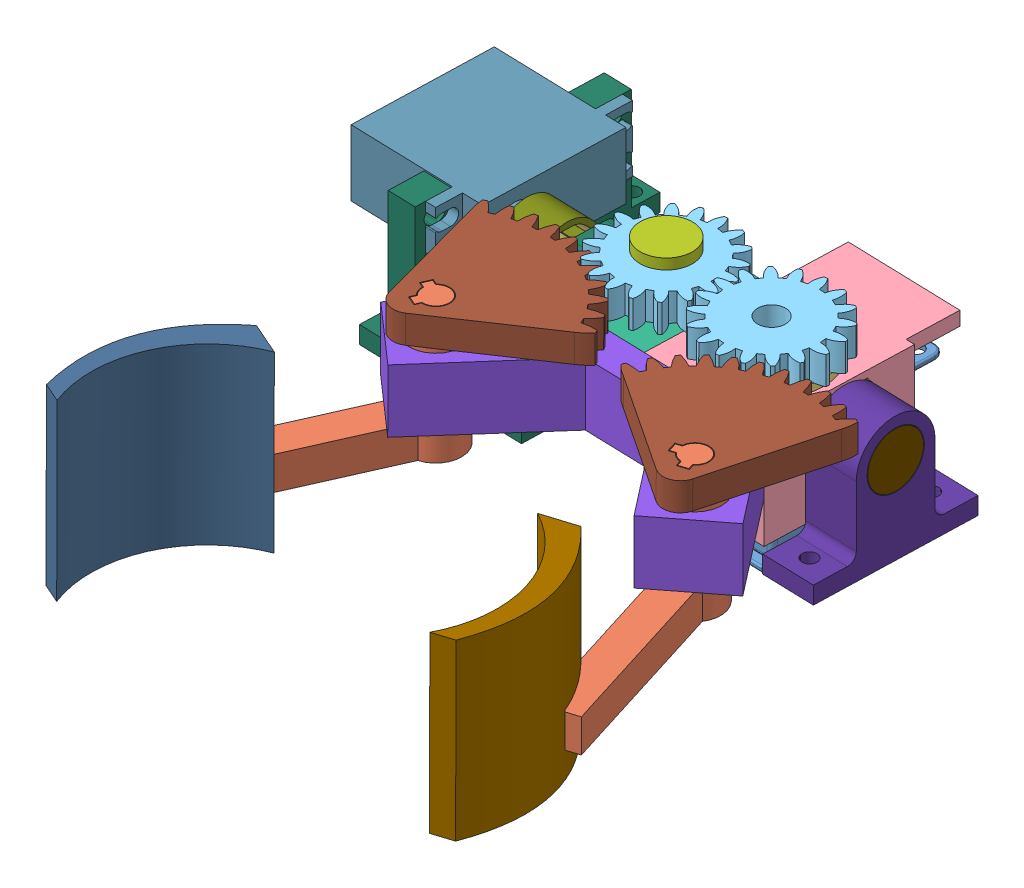
SolidWorks assembly grabber, configuration Default. Lengths in mm.
Overall size (169.93 60.06 188.53).
21 component instances, 18 part files, 50 mates.
Components (placement in the parent):
- servo-1: servo [Default] at (27.3766 37.9573 15.2032) x (0.029481 -0.000434 -0.999565) z (0.999565 0 0.029481) size (56.4 46.15 25.5)
- arm_things-1: arm_things [Default] at (68.0393 35.6063 98.6432) x (-0.953787 0.000799 0.300482) z (-0.300483 -0.002298 -0.953784) size (14.9 36.5 66.45)
- arm_things-2: arm_things [Default] at (-29.4467 35.6051 95.2471) x (-0.915399 -0.000913 -0.402546) z (0.402547 -0.002255 -0.915397) size (14.9 36.5 66.45)
- smol_white_disc_thing-1: smol_white_disc_thing [Default] at (37.0542 61.332 26.2832) x (0.993414 -0.000062 -0.11458) z (0.11458 0.00043 0.993414) size (30 3.9 30)
- servo_mount-1: servo_mount [Default] at (18.3812 44.8063 14.9167) x (0.999565 0 0.029481) z (-0.029481 0.002433 0.999562) size (35.55 36.2 57.02)
- spur gear_iso-3: spur gear_iso [ISO - Spur gear 1.75M 18T 20PA 8mmFW ---S18A75H50L8.0N] at (37.0542 65.232 26.2815) x (0.000013 1 -0.000434) z (-0.997235 -0.000019 -0.074312) size (8 34.62 35)
- spur gear_iso-4: spur gear_iso [ISO - Spur gear 1.75M 18T 20PA 8mmFW ---S18A75H50L8.0N] at (5.8572 64.9327 25.3831) x (0.000072 0.999997 -0.002432) z (0.987046 0.000319 0.160439) size (8 34.62 35)
- servo_primary_gear_mount_thingy-1: servo_primary_gear_mount_thingy [Default] at (8.2401 58.24 43.1074) x (-0.999565 0 -0.029481) z (0.029481 -0.002433 -0.999562) size (27.5 27.5 35)
- pin_dongley-1: pin_dongley [Default] at (5.8279 67.515 27.4291) x (0.999897 -0.000037 0.01435) z (-0.014349 0.002433 0.999894) size (15 17 15)
- big_gear_sticky_thing-1: big_gear_sticky_thing [Default] at (22.8275 45.0127 58.8056) x (0.999565 0 0.029481) z (-0.029481 0.002433 0.999562) size (107.35 18 41.03)
- left_grabby_hand-1: left_grabby_hand [Default] at (41.9504 28.2179 143.7732) x (-0.953787 0.000799 0.300482) z (-0.300483 -0.002298 -0.953784) size (16.77 50 47.38)
- right_grabby_hand-1: right_grabby_hand [Default] at (-8.4259 28.2196 142.9495) x (-0.915399 -0.000913 -0.402546) z (0.402547 -0.002255 -0.915397) size (16.77 50 47.38)
- big_boi_gear_left-1: big_boi_gear_left [Default] at (60.0564 65.2677 59.5235) x (0.000072 0.999997 -0.002432) z (0.953787 -0.000799 -0.300482) size (8 45.26 52.07)
- big_boi_gear_left-2: big_boi_gear_left [Default] at (-9.718 65.2752 60.5437) x (0.000072 0.999997 -0.002432) z (0.915399 0.000913 0.402546) size (8 45.26 52.07)
- right_side_axle-1: right_side_axle [Default] at (-1.8251 52.724 21.6147) x (-0.999565 0 -0.029481) z (0.029481 -0.002433 -0.999562) size (26 15.6 15.6)
- seamuing_25kg_servo_fitting-1: seamuing_25kg_servo_fitting [Default] at (-39.4398 52.7576 34.1111) x (0.000072 0.999997 -0.002432) z (0.029481 -0.002433 -0.999562) size (14.8 6 35)
- seamuing_25kg_servo_rough-1: seamuing_25kg_servo_rough [Default] at (-81.4601 52.7211 8.061) x (0.029481 -0.000265 -0.999565) z (-0.000008 -1 0.000265) size (55 47 19)
- axle_mount_right-2: axle_mount_right [Default] at (-59.5969 50.8365 13.0242) x (0.029481 -0.000265 -0.999565) z (0.999565 0 0.029481) size (76.4 34.5 48)
- servo_fitting_attachment-1: servo_fitting_attachment [Default] at (-27.0382 52.724 20.6709) x (-0.999565 0 -0.029481) z (0.029481 -0.002433 -0.999562) size (17 18.5 39.79)
- axle_mount_left-1: axle_mount_left [Default] at (55.2001 40.224 23.2966) x (0.999565 0 0.029481) z (-0.029481 0 0.999565) size (15 36 46)
- axle_left-1: axle_left [Default] at (47.2036 52.724 23.0607) x (0.999565 0 0.029481) z (-0.029481 0.002433 0.999562) size (23 15.6 15.6)
Mates (geometry in assembly coordinates):
- Coincident8: coincident anti-aligned: line of servo-1 through (37.0542 64.362 26.2819) axis (-0.000013 -1 0.000434); line of smol_white_disc_thing-1 through (37.0542 61.332 26.2832) axis (0.000013 1 -0.000434)
- Coincident10: coincident anti-aligned: plane of servo-1 through (37.0542 64.362 26.2819) normal (0.000013 1 -0.000434); plane of smol_white_disc_thing-1 through (37.0542 64.362 26.2819) normal (-0.000013 -1 0.000434)
- Coincident11: coincident aligned: line of servo-1 through (24.6003 30.6467 -9.3861) axis (-0.999565 0 -0.029481); line of servo_mount-1 through (23.101 30.6467 -9.4304) axis (-0.999565 0 -0.029481)
- Distance1: distance = 0.1 mm: line of servo_mount-1 through (21.6558 30.766 39.5682) axis (-0.999565 0 -0.029481); line of servo-1 through (23.1558 30.6679 39.5926) axis (-0.999565 0 -0.029481)
- Coincident12: coincident anti-aligned: plane of servo-1 through (22.3788 37.9573 15.0558) normal (-0.999565 0 -0.029481); plane of servo_mount-1 through (22.3794 44.8063 15.0346) normal (0.999565 0 0.029481)
- Coincident15: coincident anti-aligned: line of smol_white_disc_thing-1 through (37.0542 63.232 26.2824) axis (0.000013 1 -0.000434); line of spur gear_iso-3 through (37.0543 73.232 26.278) axis (-0.000013 -1 0.000434)
- Coincident16: coincident anti-aligned: plane of smol_white_disc_thing-1 through (37.0542 65.232 26.2815) normal (0.000013 1 -0.000434); plane of spur gear_iso-3 through (37.0542 65.232 26.2815) normal (-0.000013 -1 0.000434)
- Coincident17: coincident aligned: line of servo_mount-1 through (19.223 62.8368 -13.6249) axis (-0.029481 0.002433 0.999562); line of servo_primary_gear_mount_thingy-1 through (18.5738 62.8904 8.3855) axis (-0.029481 0.002433 0.999562)
- Coincident18: coincident aligned: line of servo_mount-1 through (17.542 62.9756 43.3702) axis (-0.000072 -0.999997 0.002432); line of servo_primary_gear_mount_thingy-1 through (17.542 62.9756 43.3702) axis (-0.000072 -0.999997 0.002432)
- Coincident23: coincident anti-aligned: plane of servo_primary_gear_mount_thingy-1 through (5.8568 59.9327 25.3952) normal (0.000072 0.999997 -0.002432); plane of pin_dongley-1 through (5.8037 59.9417 29.0948) normal (-0.000072 -0.999997 0.002432)
- Coincident25: coincident aligned: line of servo_primary_gear_mount_thingy-1 through (5.8568 59.9327 25.3952) axis (0.000072 0.999997 -0.002432); line of pin_dongley-1 through (5.8568 59.9327 25.3952) axis (0.000072 0.999997 -0.002432)
- Coincident29: coincident anti-aligned: line of spur gear_iso-4 through (5.8577 72.9327 25.3636) axis (-0.000072 -0.999997 0.002432); line of pin_dongley-1 through (5.8568 59.9327 25.3952) axis (0.000072 0.999997 -0.002432)
- Coincident30: coincident anti-aligned: plane of spur gear_iso-4 through (5.8572 64.9327 25.3831) normal (-0.000072 -0.999997 0.002432); plane of servo_primary_gear_mount_thingy-1 through (5.8572 64.9327 25.3831) normal (0.000072 0.999997 -0.002432)
- GearMate1: gear = 18 : 18 mm: line of spur gear_iso-3 through (37.0543 73.232 26.278) axis (-0.000013 -1 0.000434); line of spur gear_iso-4 through (5.8577 72.9327 25.3636) axis (-0.000072 -0.999997 0.002432)
- Coincident33: coincident aligned: line of servo_mount-1 through (53.0765 62.9756 44.4182) axis (-0.000072 -0.999997 0.002432); line of big_gear_sticky_thing-1 through (53.0765 62.9756 44.4182) axis (-0.000072 -0.999997 0.002432)
- Coincident34: coincident aligned: line of servo_mount-1 through (53.0765 62.9756 44.4182) axis (-0.999565 0 -0.029481); line of big_gear_sticky_thing-1 through (53.0765 62.9756 44.4182) axis (-0.999565 0 -0.029481)
- Coincident43: coincident anti-aligned: line of arm_things-1 through (59.1757 45.0385 70.4834) axis (0.000072 0.999997 -0.002432); line of big_gear_sticky_thing-1 through (59.177 63.0384 70.4396) axis (-0.000072 -0.999997 0.002432)
- Coincident45: coincident anti-aligned: plane of arm_things-1 through (68.04 45.1063 98.6201) normal (0.000072 0.999997 -0.002432); plane of big_gear_sticky_thing-1 through (22.8275 45.0127 58.8056) normal (-0.000072 -0.999997 0.002432)
- Coincident46: coincident anti-aligned: line of arm_things-1 through (72.3737 45.1779 128.184) axis (-0.000072 -0.999997 0.002432); line of left_grabby_hand-1 through (72.3731 35.6779 128.2071) axis (0.000072 0.999997 -0.002432)
- Coincident47: coincident anti-aligned: line of arm_things-1 through (56.3691 35.5555 77.4079) axis (0.300483 0.002298 0.953784); line of left_grabby_hand-1 through (72.3731 35.6779 128.2071) axis (-0.300483 -0.002298 -0.953784)
- Coincident48: coincident aligned: line of arm_things-2 through (-36.973 45.1759 124.1403) axis (-0.000072 -0.999997 0.002432); line of right_grabby_hand-1 through (-36.973 45.6759 124.1391) axis (-0.000072 -0.999997 0.002432)
- Coincident49: coincident aligned: line of arm_things-2 through (-36.9737 35.6759 124.1634) axis (0.402547 -0.002255 -0.915397); line of right_grabby_hand-1 through (-36.9737 35.6759 124.1634) axis (0.402547 -0.002255 -0.915397)
- Coincident50: coincident anti-aligned: line of arm_things-2 through (-17.5709 45.0385 68.2198) axis (0.000072 0.999997 -0.002432); line of big_gear_sticky_thing-1 through (-17.5696 63.0384 68.1761) axis (-0.000072 -0.999997 0.002432)
- Coincident51: coincident anti-aligned: plane of arm_things-2 through (-29.446 45.105 95.224) normal (0.000072 0.999997 -0.002432); plane of big_gear_sticky_thing-1 through (22.8275 45.0127 58.8056) normal (-0.000072 -0.999997 0.002432)
- Coincident52: coincident aligned: line of arm_things-1 through (59.1777 72.0384 70.4177) axis (-0.000072 -0.999997 0.002432); line of big_boi_gear_left-1 through (59.1777 72.0384 70.4177) axis (-0.000072 -0.999997 0.002432)
- Coincident54: coincident anti-aligned: plane of arm_things-1 through (59.1771 64.0384 70.4372) normal (0.000072 0.999997 -0.002432); plane of big_boi_gear_left-1 through (59.1771 64.0384 70.4372) normal (-0.000072 -0.999997 0.002432)
- Parallel1: parallel aligned: line of arm_things-1 through (59.4915 72.0513 75.7401) axis (0.953787 -0.000799 -0.300482); line of big_boi_gear_left-1 through (59.3696 72.052 76.0189) axis (0.953787 -0.000799 -0.300482)
- Coincident57: coincident aligned: line of arm_things-1 through (59.1777 72.0384 70.4177) axis (-0.000072 -0.999997 0.002432); line of big_boi_gear_left-1 through (59.1777 72.0384 70.4177) axis (-0.000072 -0.999997 0.002432)
- GearMate6: gear = 38 : 18 mm: line of spur gear_iso-3 through (37.0543 73.232 26.278) axis (-0.000013 -1 0.000434); line of big_boi_gear_left-1 through (59.1777 72.0384 70.4177) axis (-0.000072 -0.999997 0.002432)
- Coincident59: coincident aligned: line of arm_things-2 through (-17.569 72.0384 68.1542) axis (-0.000072 -0.999997 0.002432); line of big_boi_gear_left-2 through (-17.569 72.0384 68.1542) axis (-0.000072 -0.999997 0.002432)
- Coincident60: coincident anti-aligned: plane of arm_things-2 through (-17.5695 64.0384 68.1736) normal (0.000072 0.999997 -0.002432); plane of big_boi_gear_left-2 through (-17.5695 64.0384 68.1736) normal (-0.000072 -0.999997 0.002432)
- GearMate9: gear = 38 : 18 mm: line of spur gear_iso-4 through (5.8577 72.9327 25.3636) axis (-0.000072 -0.999997 0.002432); line of big_boi_gear_left-2 through (-17.569 72.0384 68.1542) axis (-0.000072 -0.999997 0.002432)
- Parallel4: parallel anti-aligned: line of arm_things-2 through (-20.8404 72.0489 72.3641) axis (0.915399 0.000913 0.402546); line of big_boi_gear_left-2 through (-18.3702 64.052 73.7206) axis (-0.915399 -0.000913 -0.402546)
- Coincident61: coincident anti-aligned: line of servo_primary_gear_mount_thingy-1 through (-2.0674 44.944 29.83) axis (0.029481 -0.002433 -0.999562); line of right_side_axle-1 through (-1.5957 44.9051 13.837) axis (-0.029481 0.002433 0.999562)
- Coincident62: coincident anti-aligned: line of servo_primary_gear_mount_thingy-1 through (-1.5957 44.9051 13.837) axis (0.000072 0.999997 -0.002432); line of right_side_axle-1 through (-1.5946 60.505 13.7991) axis (-0.000072 -0.999997 0.002432)
- Coincident65: coincident aligned: line of seamuing_25kg_servo_fitting-1 through (-33.0356 52.724 20.494) axis (-0.999565 0 -0.029481); line of seamuing_25kg_servo_rough-1 through (-34.8048 52.724 20.4419) axis (-0.999565 0 -0.029481)
- Coincident66: coincident anti-aligned: plane of seamuing_25kg_servo_fitting-1 through (-39.4398 52.7576 34.1111) normal (-0.999565 0 -0.029481); plane of seamuing_25kg_servo_rough-1 through (-39.033 52.724 20.3172) normal (0.999565 0 0.029481)
- Coincident67: coincident anti-aligned: line of seamuing_25kg_servo_rough-1 through (-50.7508 57.7146 -15.5452) axis (0.999565 0 0.029481); line of axle_mount_right-2 through (-50.7508 57.7146 -15.5452) axis (-0.999565 0 -0.029481)
- Distance2: distance = 0.4 mm: line of seamuing_25kg_servo_rough-1 through (-52.1954 57.7276 33.4335) axis (0.999565 0 0.029481); line of axle_mount_right-2 through (-52.2072 57.7277 33.8333) axis (-0.999565 0 -0.029481)
- Coincident69: coincident anti-aligned: plane of seamuing_25kg_servo_rough-1 through (-53.0722 43.2355 63.1598) normal (-0.999565 0 -0.029481); plane of axle_mount_right-2 through (-51.6004 50.8365 13.26) normal (0.999565 0 0.029481)
- Coincident72: coincident aligned: line of right_side_axle-1 through (-27.8138 52.724 20.8481) axis (0.999565 0 0.029481); line of axle_mount_right-2 through (-21.8164 52.724 21.025) axis (0.999565 0 0.029481)
- Coincident73: coincident anti-aligned: plane of right_side_axle-1 through (-11.8207 52.724 21.3198) normal (-0.999565 0 -0.029481); plane of axle_mount_right-2 through (-11.6178 50.8365 14.4393) normal (0.999565 0 0.029481)
- Coincident74: coincident aligned: line of seamuing_25kg_servo_fitting-1 through (-33.0356 52.724 20.494) axis (-0.999565 0 -0.029481); line of servo_fitting_attachment-1 through (-27.0382 52.724 20.6709) axis (-0.999565 0 -0.029481)
- Parallel9: parallel anti-aligned: line of seamuing_25kg_servo_fitting-1 through (-33.7503 56.133 44.7253) axis (0.029481 -0.002433 -0.999562); line of servo_fitting_attachment-1 through (-39.2401 58.7411 27.3395) axis (-0.029481 0.002433 0.999562)
- Coincident75: coincident anti-aligned: plane of seamuing_25kg_servo_fitting-1 through (-33.4424 52.7576 34.288) normal (0.999565 0 0.029481); plane of servo_fitting_attachment-1 through (-33.0356 52.724 20.494) normal (-0.999565 0 -0.029481)
- Parallel13: parallel anti-aligned: line of right_side_axle-1 through (-22.3939 50.7057 13.4704) axis (-0.029481 0.002433 0.999562); line of servo_fitting_attachment-1 through (-21.957 54.5671 17.9923) axis (0.029481 -0.002433 -0.999562)
- Coincident81: coincident anti-aligned: line of servo_mount-1 through (47.433 44.9051 15.2831) axis (0.999565 0 0.029481); line of axle_left-1 through (55.4295 44.9051 15.5189) axis (-0.999565 0 -0.029481)
- Coincident82: coincident anti-aligned: line of servo_mount-1 through (47.434 58.905 15.249) axis (-0.000072 -0.999997 0.002432); line of axle_left-1 through (47.433 44.9051 15.2831) axis (0.000072 0.999997 -0.002432)
- Coincident83: coincident aligned: line of axle_mount_left-1 through (70.1936 52.724 23.7388) axis (-0.999565 0 -0.029481); line of axle_left-1 through (70.1936 52.724 23.7388) axis (-0.999565 0 -0.029481)
- Coincident84: coincident anti-aligned: plane of axle_mount_left-1 through (55.2001 52.724 23.2966) normal (-0.999565 0 -0.029481); plane of axle_left-1 through (55.2001 52.724 23.2966) normal (0.999565 0 0.029481)
